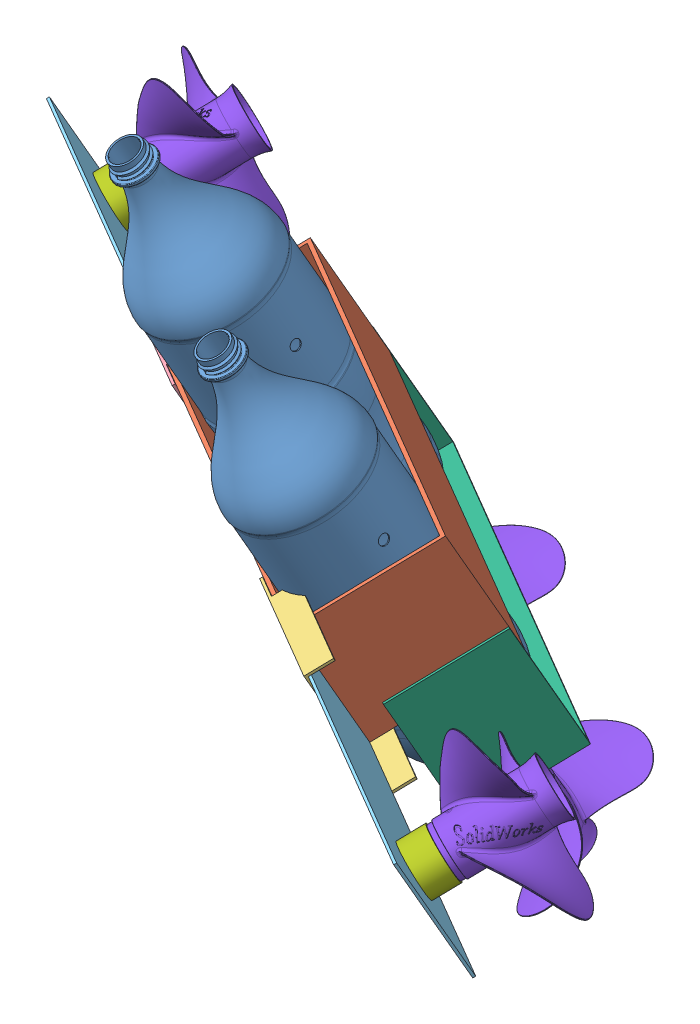
SolidWorks assembly AUV_Assembly_final_1a, configuration Default. Lengths in mm.
Overall size (1002.23 550.38 731.46).
19 component instances, 9 part files, 45 mates.
Components (placement in the parent):
- 2l_cola_bottle-1: 2l_cola_bottle [Standard] at (-3499.4385 1138.2841 -424.9238) x (0.971438 0.2034 0.122213) z (-0.025048 -0.42426 0.905194) size (104.49 326.54 105)
- Square_section-1: Square_section [Default] at (-3127.0335 1252.5897 -290.5609) x (-0.863397 0.001848 -0.504521) z (0.445942 0.470494 -0.761427) size (306 100 106.24)
- 2l_cola_bottle-2: 2l_cola_bottle [Standard] at (-3326.9688 1137.9149 -324.1421) x (0.971438 0.2034 0.122213) z (-0.025048 -0.42426 0.905194) size (104.49 326.54 105)
- Lplate-2: Lplate [Default] at (-3387.6151 1201.7685 -336.3637) x (-0.235967 0.882401 0.407047) z (-0.863397 0.001848 -0.504521) size (20 20 100)
- Lplate_2-2: Lplate_2 [Default] at (-3498.4954 1293.723 -344.4829) x (0.235967 -0.882401 -0.407047) z (0.863397 -0.001848 0.504521) size (20 20 100)
- Rectangular_plate-3: Rectangular_plate [Default] at (-3434.682 1204.5759 -364.8211) x (-0.863397 0.001848 -0.504521) z (0.445942 0.470494 -0.761427) size (240 100 2)
- C_section-1: C_section [Default] at (-3406.3328 1143.9771 -413.5576) x (-0.235967 0.882401 0.407047) z (0.445942 0.470494 -0.761427) size (102 310 85)
- Motor_substitute-1: Motor_substitute [Default] at (-3168.5896 1139.097 -319.2055) x (-0.398726 -0.469909 0.78753) z (-0.235967 0.882401 0.407047) size (40 40 20)
- Motor_substitute-2: Motor_substitute [Default] at (-3600.7151 1259.398 -457.0792) x (0.585249 -0.796921 -0.149665) z (-0.445942 -0.470494 0.761427) size (40 40 20)
- Motor_substitute-3: Motor_substitute [Default] at (-3341.0593 1139.4661 -419.9872) x (0.971438 0.2034 0.122213) z (-0.235967 0.882401 0.407047) size (40 40 20)
- Motor_substitute-4: Motor_substitute [Default] at (-3017.3434 1248.7203 -95.7491) x (0.879921 -0.386256 0.276669) z (0.445942 0.470494 -0.761427) size (40 40 20)
- Part1^AUV_Assembly_final_1a-1: Part1^AUV_Assembly_final_1a [Default] at origin (virtual)
- Προπέλα τελικό-1: Προπέλα τελικό [Default] at (-3159.9741 1106.9884 -334.0294) x (0.971438 0.2034 0.122213) z (-0.235967 0.882401 0.407047) size (302.99 302.99 150)
- Προπέλα τελικό-2: Προπέλα τελικό [Default] at (-3332.4438 1107.3576 -434.811) x (0.971438 0.2034 0.122213) z (-0.235967 0.882401 0.407047) size (302.99 302.99 150)
- Προπέλα τελικό-3: Προπέλα τελικό [Default] at (-2992.1711 1275.2651 -138.6752) x (0.875367 -0.051781 0.480677) z (-0.445942 -0.470494 0.761427) size (302.99 302.99 150)
- Rectangular_plate-4: Rectangular_plate [Default] at (-3169.5905 1204.9514 -211.9605) x (0.863397 -0.001848 0.504521) z (-0.445942 -0.470494 0.761427) size (240 100 2)
- Lplate-3: Lplate [Default] at (-3241.203 1293.1723 -194.1356) x (0.235967 -0.882401 -0.407047) z (0.863397 -0.001848 0.504521) size (20 20 100)
- Lplate-4: Lplate [Default] at (-3214.0722 1201.397 -234.955) x (0.445942 0.470494 -0.761427) z (0.863397 -0.001848 0.504521) size (20 20 100)
- Προπέλα τελικό-4: Προπέλα τελικό [Default] at (-3584.5033 1276.545 -484.7936) x (-0.402667 0.865207 0.298792) z (-0.445942 -0.470494 0.761427) size (302.99 302.99 150)
Mates (geometry in assembly coordinates):
- Coincident86: coincident: plane of Lplate_2-2 through (-3410.7918 1292.7144 -296.3678) normal (0.445942 0.470494 -0.761427); plane of Rectangular_plate-3 through (-3434.682 1204.5759 -364.8211) normal (-0.445942 -0.470494 0.761427)
- Coincident87: coincident: plane of Lplate_2-2 through (-3410.7918 1292.7144 -296.3678) normal (0.235967 -0.882401 -0.407047); plane of Rectangular_plate-3 through (-3457.3868 1293.757 -325.6393) normal (-0.235967 0.882401 0.407047)
- Coincident88: coincident: plane of Square_section-1 through (-3458.2787 1292.8161 -324.1164) normal (-0.863397 0.001848 -0.504521); plane of Rectangular_plate-3 through (-3433.7901 1205.5169 -366.344) normal (0.863397 -0.001848 0.504521)
- Coincident89: coincident: plane of Square_section-1 through (-3150.6302 1340.8299 -249.8562) normal (-0.235967 0.882401 0.407047); plane of Lplate_2-2 through (-3410.7918 1292.7144 -296.3678) normal (0.235967 -0.882401 -0.407047)
- Coincident90: coincident: plane of Square_section-1 through (-3194.0791 1292.2505 -169.7329) normal (-0.445942 -0.470494 0.761427); plane of Lplate_2-2 through (-3410.7918 1292.7144 -296.3678) normal (0.445942 0.470494 -0.761427)
- Coincident91: coincident: plane of Lplate-2 through (-3473.5349 1204.6591 -387.5246) normal (0.445942 0.470494 -0.761427); plane of Rectangular_plate-3 through (-3434.682 1204.5759 -364.8211) normal (-0.445942 -0.470494 0.761427)
- Coincident92: coincident: plane of Square_section-1 through (-3127.0335 1252.5897 -290.5609) normal (0.235967 -0.882401 -0.407047); plane of Lplate-2 through (-3473.5349 1204.6591 -387.5246) normal (-0.235967 0.882401 0.407047)
- Distance11: distance = 45 mm: plane of Square_section-1 through (-3458.2787 1292.8161 -324.1164) normal (-0.863397 0.001848 -0.504521); plane of Lplate-2 through (-3473.9548 1201.9533 -386.8158) normal (-0.863397 0.001848 -0.504521)
- Distance12: distance = 45 mm: plane of Square_section-1 through (-3458.2787 1292.8161 -324.1164) normal (-0.863397 0.001848 -0.504521); plane of Lplate_2-2 through (-3498.4954 1293.723 -344.4829) normal (-0.863397 0.001848 -0.504521)
- Tangent21: tangent: plane of Square_section-1 through (-3195.3314 1293.6676 -173.5308) normal (0.445942 0.470494 -0.761427); cylinder of 2l_cola_bottle-2 through (-3257.6041 1471.968 -165.6538) axis (-0.235967 0.882401 0.407047) radius 50.1215
- Tangent22: tangent: plane of Square_section-1 through (-3150.6302 1340.8299 -249.8562) normal (-0.863397 0.001848 -0.504521); cylinder of 2l_cola_bottle-2 through (-3257.6041 1471.968 -165.6538) axis (-0.235967 0.882401 0.407047) radius 50.1215
- Tangent23: tangent: cylinder of 2l_cola_bottle-1 through (-3430.0738 1472.3372 -266.4355) axis (-0.235967 0.882401 0.407047) radius 50.1215; plane of Square_section-1 through (-3195.3314 1293.6676 -173.5308) normal (0.445942 0.470494 -0.761427)
- Tangent24: tangent: cylinder of 2l_cola_bottle-1 through (-3430.0738 1472.3372 -266.4355) axis (-0.235967 0.882401 0.407047) radius 50.1215; plane of Square_section-1 through (-3454.3507 1294.222 -324.8871) normal (0.863397 -0.001848 0.504521)
- Distance13: distance = 50 mm: point of 2l_cola_bottle-1; plane of Square_section-1 through (-3127.0335 1252.5897 -290.5609) normal (0.235967 -0.882401 -0.407047)
- Distance14: distance = 50 mm: point of 2l_cola_bottle-2; plane of Square_section-1 through (-3127.0335 1252.5897 -290.5609) normal (0.235967 -0.882401 -0.407047)
- Distance15: distance = 20 mm: plane of C_section-1 through (-3392.0244 1272.2092 -437.5742) normal (-0.235967 0.882401 0.407047); plane of Square_section-1 through (-3127.0335 1252.5897 -290.5609) normal (0.235967 -0.882401 -0.407047)
- Coincident107: coincident: plane of Square_section-1 through (-3458.2787 1292.8161 -324.1164) normal (-0.863397 0.001848 -0.504521); plane of C_section-1 through (-3368.4277 1183.9691 -478.2789) normal (0.863397 -0.001848 0.504521)
- Coincident108: coincident: plane of Square_section-1 through (-3410.9017 1342.8013 -405.0104) normal (0.445942 0.470494 -0.761427); plane of C_section-1 through (-3368.4277 1183.9691 -478.2789) normal (0.445942 0.470494 -0.761427)
- Coincident109: coincident: plane of C_section-1 through (-3369.6826 1182.208 -480.1021) normal (0.235967 -0.882401 -0.407047); plane of Motor_substitute-3 through (-3345.7786 1157.1142 -411.8462) normal (-0.235967 0.882401 0.407047)
- Coincident110: coincident: axis of 2l_cola_bottle-1 through (-3394.1207 1337.89 -328.4553) axis (-0.235967 0.882401 0.407047); axis of Motor_substitute-3 through (-3345.7786 1157.1142 -411.8462) axis (0.235967 -0.882401 -0.407047)
- Coincident111: coincident: plane of C_section-1 through (-3369.6826 1182.208 -480.1021) normal (0.235967 -0.882401 -0.407047); plane of Motor_substitute-1 through (-3173.3089 1156.745 -311.0646) normal (-0.235967 0.882401 0.407047)
- Coincident112: coincident: axis of 2l_cola_bottle-2 through (-3221.651 1337.5209 -227.6736) axis (-0.235967 0.882401 0.407047); axis of Motor_substitute-1 through (-3173.3089 1156.745 -311.0646) axis (0.235967 -0.882401 -0.407047)
- Coincident113: coincident: axis of Motor_substitute-3 through (-3345.7786 1157.1142 -411.8462) axis (0.235967 -0.882401 -0.407047); axis of Προπέλα τελικό-2 through (-3326.2632 1084.136 -445.5107) axis (-0.235967 0.882401 0.407047)
- Coincident115: coincident: axis of Motor_substitute-1 through (-3173.3089 1156.745 -311.0646) axis (0.235967 -0.882401 -0.407047); axis of Προπέλα τελικό-1 through (-3153.7935 1083.7668 -344.7291) axis (-0.235967 0.882401 0.407047)
- Coincident119: coincident: plane of Motor_substitute-1 through (-3168.5896 1139.097 -319.2055) normal (0.235967 -0.882401 -0.407047); plane of Προπέλα τελικό-1 through (-3168.5896 1139.097 -319.2055) normal (-0.235967 0.882401 0.407047)
- Coincident120: coincident: plane of Motor_substitute-3 through (-3341.0593 1139.4661 -419.9872) normal (0.235967 -0.882401 -0.407047); plane of Προπέλα τελικό-2 through (-3341.0593 1139.4661 -419.9872) normal (-0.235967 0.882401 0.407047)
- Coincident125: coincident: plane of Square_section-1 through (-3194.0791 1292.2505 -169.7329) normal (-0.445942 -0.470494 0.761427); plane of Rectangular_plate-4 through (-3170.4824 1204.0104 -210.4377) normal (-0.445942 -0.470494 0.761427)
- Coincident126: coincident: plane of Square_section-1 through (-3146.7022 1342.2358 -250.6269) normal (0.863397 -0.001848 0.504521); plane of Rectangular_plate-4 through (-3170.4824 1204.0104 -210.4377) normal (-0.863397 0.001848 -0.504521)
- Coincident127: coincident: plane of Square_section-1 through (-3127.0335 1252.5897 -290.5609) normal (0.235967 -0.882401 -0.407047); plane of Rectangular_plate-4 through (-2963.267 1203.5669 -89.3526) normal (0.235967 -0.882401 -0.407047)
- Coincident128: coincident: plane of Square_section-1 through (-3150.6302 1340.8299 -249.8562) normal (-0.235967 0.882401 0.407047); plane of Lplate-3 through (-3153.4994 1292.1637 -146.0205) normal (0.235967 -0.882401 -0.407047)
- Coincident129: coincident: plane of Square_section-1 through (-3194.0791 1292.2505 -169.7329) normal (-0.445942 -0.470494 0.761427); plane of Lplate-3 through (-3153.4994 1292.1637 -146.0205) normal (0.445942 0.470494 -0.761427)
- Distance17: distance = 50 mm: plane of Lplate-3 through (-3154.8632 1292.9875 -143.6835) normal (0.863397 -0.001848 0.504521); plane of Square_section-1 through (-3150.6302 1340.8299 -249.8562) normal (-0.863397 0.001848 -0.504521)
- Coincident131: coincident: plane of Square_section-1 through (-3127.0335 1252.5897 -290.5609) normal (0.235967 -0.882401 -0.407047); plane of Lplate-4 through (-3127.3125 1203.918 -185.2116) normal (-0.235967 0.882401 0.407047)
- Coincident132: coincident: plane of Square_section-1 through (-3194.0791 1292.2505 -169.7329) normal (-0.445942 -0.470494 0.761427); plane of Lplate-4 through (-3127.3125 1203.918 -185.2116) normal (0.445942 0.470494 -0.761427)
- Distance18: distance = 50 mm: plane of Lplate-4 through (-3127.7325 1201.2122 -184.5028) normal (0.863397 -0.001848 0.504521); plane of Square_section-1 through (-3146.7022 1342.2358 -250.6269) normal (0.863397 -0.001848 0.504521)
- Distance21: distance = 50 mm: axis of Motor_substitute-4 through (-3008.4245 1258.1302 -110.9777) axis (-0.445942 -0.470494 0.761427); plane of Rectangular_plate-4 through (-2986.8637 1291.807 -48.6479) normal (0.863397 -0.001848 0.504521)
- Distance22: distance = 50 mm: axis of Motor_substitute-4 through (-3008.4245 1258.1302 -110.9777) axis (-0.445942 -0.470494 0.761427); plane of Rectangular_plate-4 through (-2963.267 1203.5669 -89.3526) normal (0.235967 -0.882401 -0.407047)
- Distance23: distance = 50 mm: axis of Motor_substitute-2 through (-3609.6339 1249.9881 -441.8507) axis (0.445942 0.470494 -0.761427); plane of Rectangular_plate-3 through (-3664.6022 1294.2006 -446.7244) normal (-0.863397 0.001848 -0.504521)
- Distance25: distance = 50 mm: axis of Motor_substitute-2 through (-3609.6339 1249.9881 -441.8507) axis (0.445942 0.470494 -0.761427); plane of Rectangular_plate-3 through (-3641.0055 1205.9604 -487.4291) normal (0.235967 -0.882401 -0.407047)
- Coincident143: coincident: axis of Motor_substitute-4 through (-3008.4245 1258.1302 -110.9777) axis (-0.445942 -0.470494 0.761427); axis of Προπέλα τελικό-3 through (-2980.4621 1287.6321 -158.7222) axis (-0.445942 -0.470494 0.761427)
- Coincident144: coincident: plane of Motor_substitute-4 through (-3008.4245 1258.1302 -110.9777) normal (0.445942 0.470494 -0.761427); plane of Προπέλα τελικό-3 through (-3008.4245 1258.1302 -110.9777) normal (-0.445942 -0.470494 0.761427)
- Coincident145: coincident: plane of Motor_substitute-2 through (-3600.7151 1259.398 -457.0792) normal (0.445942 0.470494 -0.761427); plane of Προπέλα τελικό-4 through (-3600.7151 1259.398 -457.0792) normal (-0.445942 -0.470494 0.761427)
- Coincident146: coincident: axis of Motor_substitute-2 through (-3609.6339 1249.9881 -441.8507) axis (0.445942 0.470494 -0.761427); axis of Προπέλα τελικό-4 through (-3572.7527 1288.8999 -504.8238) axis (-0.445942 -0.470494 0.761427)
- Coincident147: coincident: plane of Rectangular_plate-3 through (-3433.7901 1205.5169 -366.344) normal (0.445942 0.470494 -0.761427); plane of Motor_substitute-2 through (-3609.6339 1249.9881 -441.8507) normal (-0.445942 -0.470494 0.761427)
- Coincident148: coincident: plane of Motor_substitute-4 through (-3017.3434 1248.7203 -95.7491) normal (-0.445942 -0.470494 0.761427); plane of Rectangular_plate-4 through (-3169.5905 1204.9514 -211.9605) normal (0.445942 0.470494 -0.761427)
